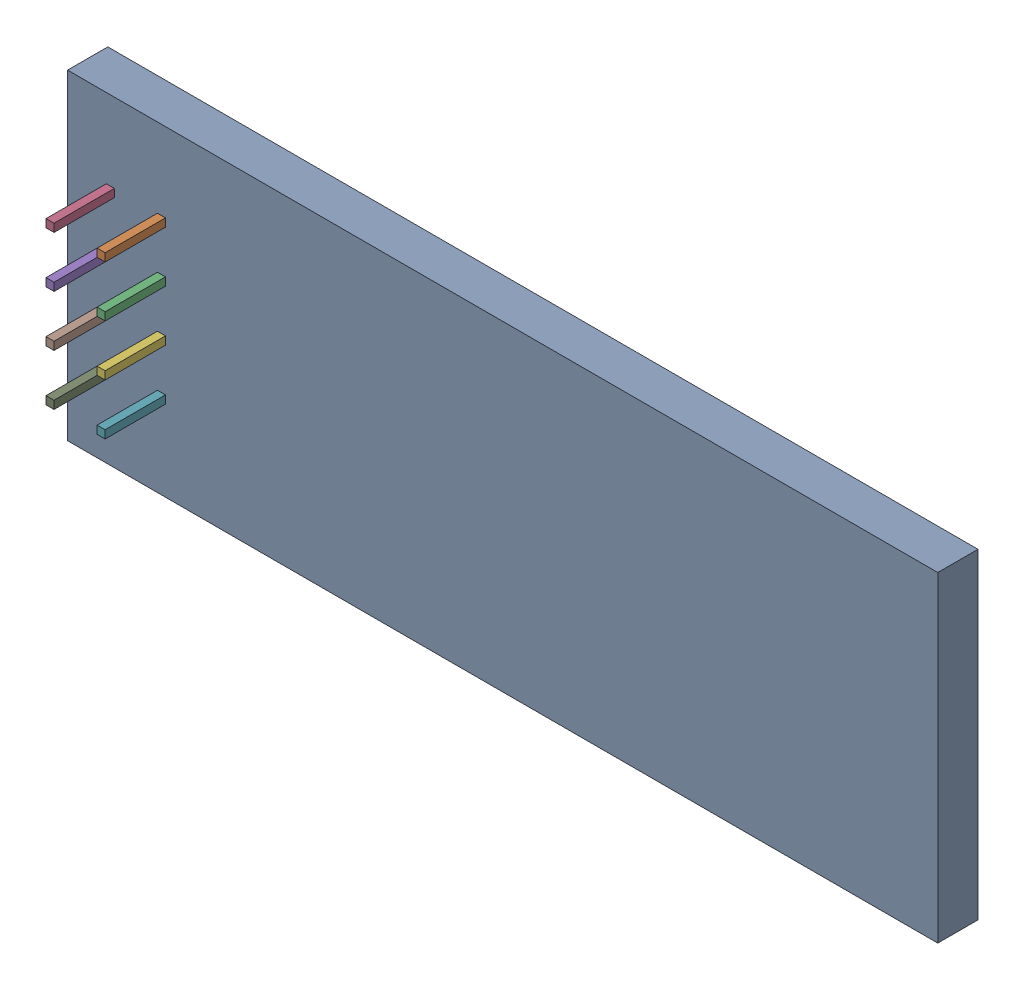
SolidWorks assembly U3, configuration Default. Lengths in mm.
Overall size (43.25 15.95 5.5).
18 component instances, 2 part files, 0 mates.
Components (placement in the parent):
- 959206080-1: 959206080 [Default] at (102.177 84.441 -2.3912) size (43.25 15.95 2)
  - Extruded-6-1: Extruded-6 [Default] at origin size (43.25 15.95 2)
- 959205944-1: 959205944 [Default] at (85.217 88.291 -2.8912) size (0.4 0.4 5.5)
  - Extruded-7-1: Extruded-7 [Default] at origin size (0.4 0.4 5.5)
- 959205944-2: 959205944 [Default] at (85.217 85.751 -2.8912) size (0.4 0.4 5.5)
  - Extruded-7-1: Extruded-7 [Default] at origin size (0.4 0.4 5.5)
- 959205944-3: 959205944 [Default] at (82.677 88.291 -2.8912) size (0.4 0.4 5.5)
  - Extruded-7-1: Extruded-7 [Default] at origin size (0.4 0.4 5.5)
- 959205944-4: 959205944 [Default] at (82.677 85.751 -2.8912) size (0.4 0.4 5.5)
  - Extruded-7-1: Extruded-7 [Default] at origin size (0.4 0.4 5.5)
- 959205944-5: 959205944 [Default] at (85.217 83.211 -2.8912) size (0.4 0.4 5.5)
  - Extruded-7-1: Extruded-7 [Default] at origin size (0.4 0.4 5.5)
- 959205944-6: 959205944 [Default] at (85.217 80.671 -2.8912) size (0.4 0.4 5.5)
  - Extruded-7-1: Extruded-7 [Default] at origin size (0.4 0.4 5.5)
- 959205944-7: 959205944 [Default] at (82.677 83.211 -2.8912) size (0.4 0.4 5.5)
  - Extruded-7-1: Extruded-7 [Default] at origin size (0.4 0.4 5.5)
- 959205944-8: 959205944 [Default] at (82.677 80.671 -2.8912) size (0.4 0.4 5.5)
  - Extruded-7-1: Extruded-7 [Default] at origin size (0.4 0.4 5.5)
